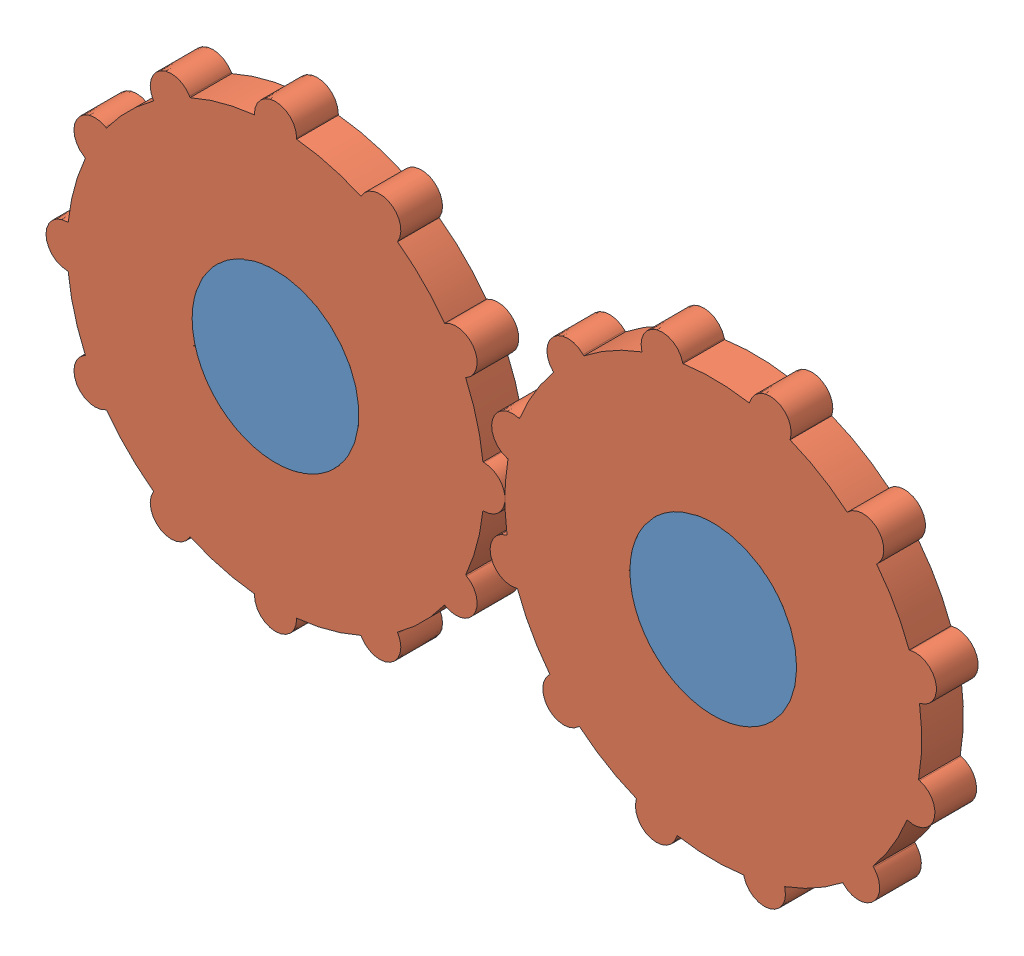
SolidWorks assembly Assem2, configuration Default. Lengths in mm.
Overall size (228.03 135.94 10).
3 component instances, 2 part files, 4 mates.
Components (placement in the parent):
- plane_3d_2-1: plane_3d_2 [Default] at (-8.9437 3.3896 140) size (145 40 10)
- gear_3d-1: gear_3d [Default] at (-60.3127 -1.6413 140) size (110.11 110.11 10)
- gear_3d-2: gear_3d [Default] at (44.6873 -1.6413 140) x (0.962188 -0.272386 0) z (0 0 1) size (110.11 110.11 10)
Mates (geometry in assembly coordinates):
- Coincident1: coincident aligned: plane of plane_3d_2-1 through (-8.9437 3.3896 150) normal (0 0 1); plane of gear_3d-1 through (-60.3127 -1.6413 150) normal (0 0 1)
- Coincident2: coincident aligned: plane of plane_3d_2-1 through (-8.9437 3.3896 150) normal (0 0 1); plane of gear_3d-2 through (44.6873 -1.6413 150) normal (0 0 1)
- Coincident3: coincident aligned: circle of plane_3d_2-1; circle of gear_3d-1
- Coincident4: coincident aligned: circle of plane_3d_2-1; circle of gear_3d-2
